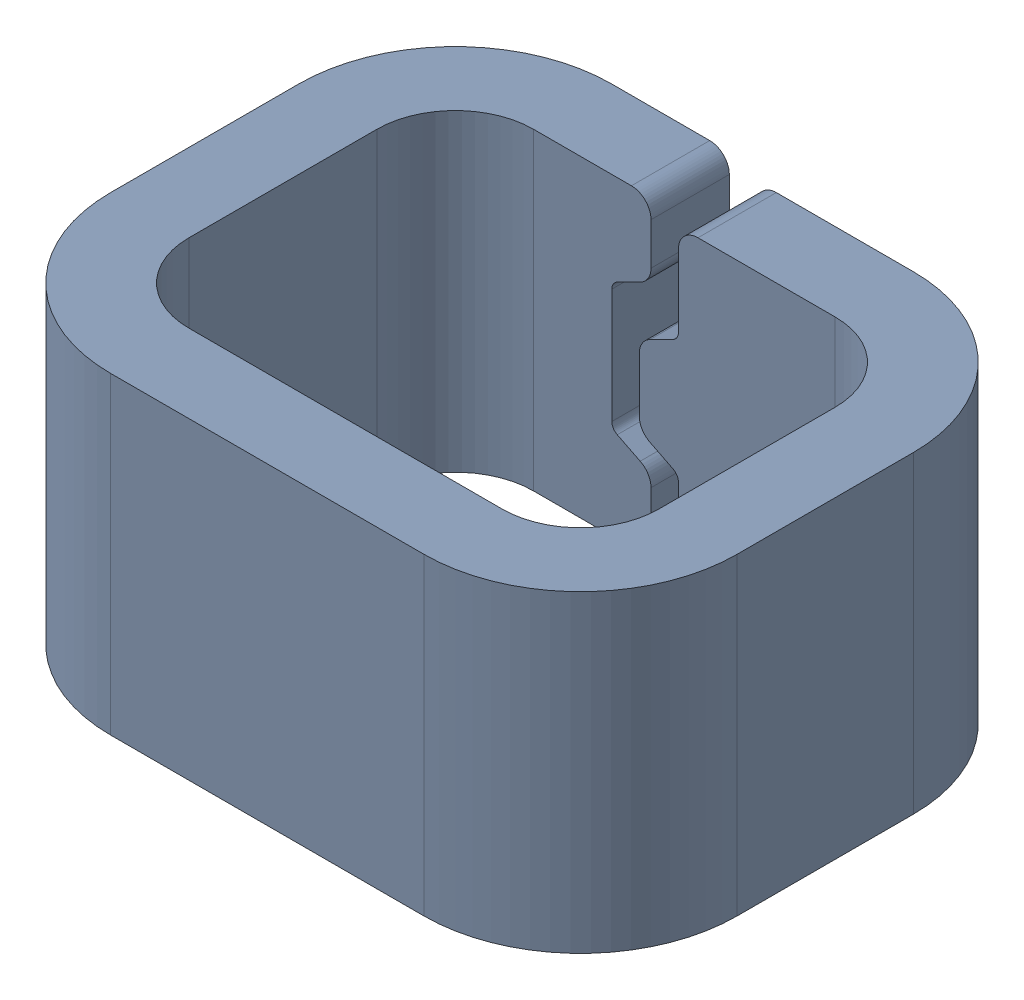
SolidWorks assembly TP2, configuration Default. Lengths in mm.
Overall size (1.6 0.8 1.28).
2 component instances, 1 part files, 0 mates.
Components (placement in the parent):
- Conn_Harwin_S2761-46R_eec-1: Conn_Harwin_S2761-46R_eec [Default] at (22.606 8.255 0) x (-1 0 0) z (0 0 1) size (1.6 0.8 1.28)
  - TP-1: TP [Default] at origin size (1.6 0.8 1.28)
